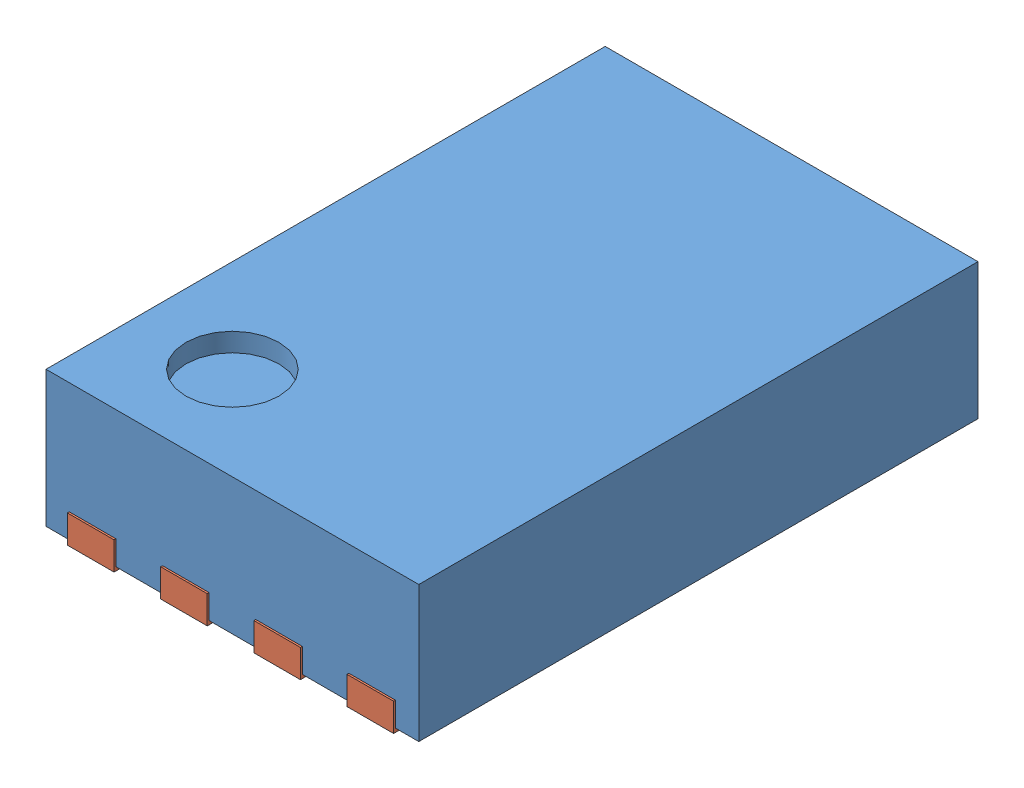
SolidWorks assembly CP-8-4, configuration Default. Lengths in mm.
Overall size (2 0.75 3.02).
10 component instances, 3 part files, 9 mates.
Components (placement in the parent):
- Body-1: Body [Default] at (0 0.02 0) size (2 0.73 3)
- P-1: P [Default] at (0.75 0 -1.305) x (0 0 1) z (-1 0 0) size (0.41 0.15 0.25)
- P-2: P [Default] at (0.25 0 -1.305) x (0 0 1) z (-1 0 0) size (0.41 0.15 0.25)
- P-3: P [Default] at (-0.25 0 -1.305) x (0 0 1) z (-1 0 0) size (0.41 0.15 0.25)
- P-4: P [Default] at (-0.75 0 -1.305) x (0 0 1) z (-1 0 0) size (0.41 0.15 0.25)
- P-5: P [Default] at (0.75 0 1.305) x (0 0 -1) z (1 0 0) size (0.41 0.15 0.25)
- P-6: P [Default] at (0.25 0 1.305) x (0 0 -1) z (1 0 0) size (0.41 0.15 0.25)
- P-7: P [Default] at (-0.25 0 1.305) x (0 0 -1) z (1 0 0) size (0.41 0.15 0.25)
- P-8: P [Default] at (-0.75 0 1.305) x (0 0 -1) z (1 0 0) size (0.41 0.15 0.25)
- EP-1: EP [Default] at (0 0.15 0) x (-1 0 0) z (0 0 1) size (1.65 0.15 1.8)
Mates (geometry in assembly coordinates):
- Coincident1: coincident: plane of Body-1 through (0 0.02 0) normal (0 0 1); plane of assembly through (0 0 0) normal (0 0 1)
- Coincident2: coincident: plane of Body-1 through (0 0.02 0) normal (1 0 0); plane of assembly through (0 0 0) normal (1 0 0)
- Distance1: distance = 0.02 mm: plane of assembly through (0 0 0) normal (0 1 0); plane of Body-1 through (0 0.02 0) normal (0 -1 0)
- Coincident4: coincident: plane of P-1 through (0.75 0 -1.305) normal (0 -1 0); plane of assembly through (0 0 0) normal (0 1 0)
- Distance2: distance = 0.01 mm: plane of P-1 through (0.625 0.15 -1.51) normal (0 0 -1); plane of Body-1 through (-1 0.75 -1.5) normal (0 0 -1)
- Distance3: distance = 0.75 mm: plane of P-1 through (0.75 0 -1.305) normal (-1 0 0); plane of assembly through (0 0 0) normal (1 0 0)
- Coincident6: coincident: plane of P-5 through (0.75 0 1.305) normal (0 -1 0); plane of EP-1 through (0 0 0) normal (0 -1 0)
- Coincident7: coincident: plane of EP-1 through (0 0.15 0) normal (0 0 1); plane of assembly
- Coincident8: coincident: plane of EP-1 through (0 0.15 0) normal (-1 0 0); plane of assembly
